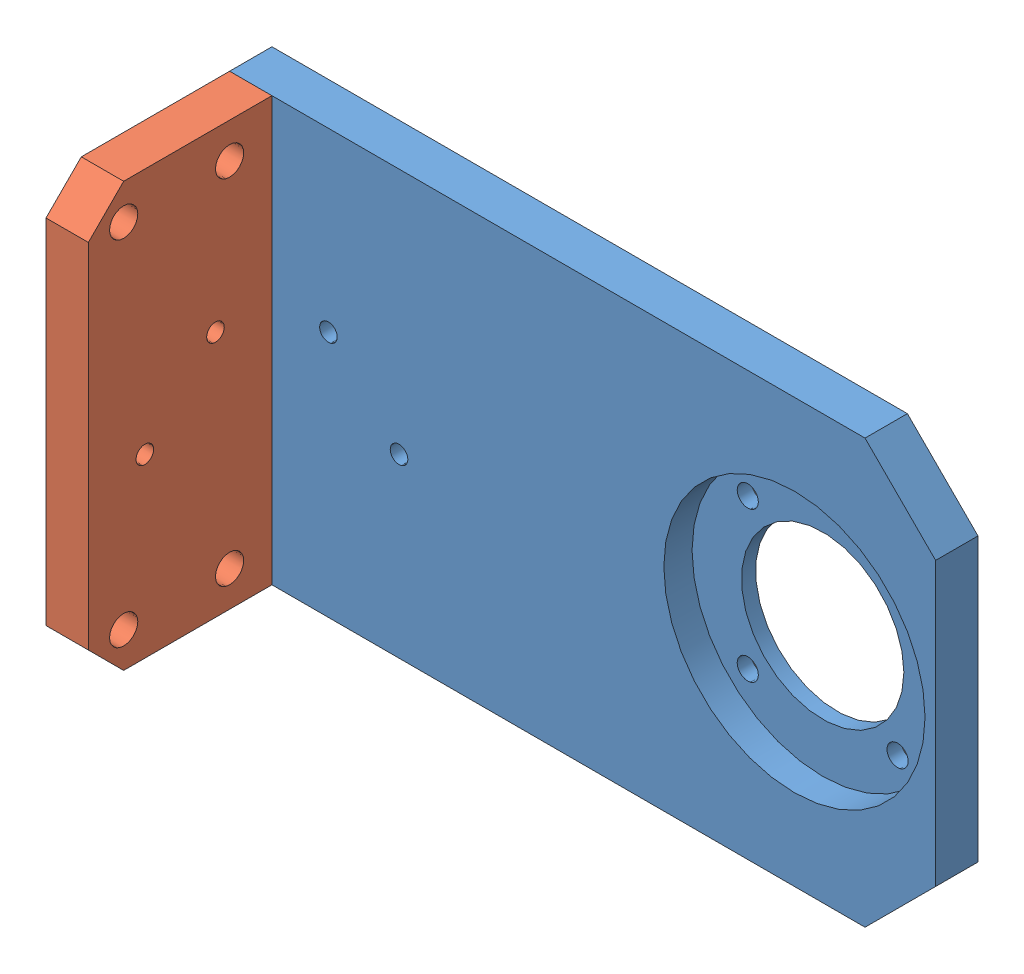
SolidWorks assembly 左右电机安装板, configuration 默认. Lengths in mm.
Overall size (100 60 32.22).
2 component instances, 2 part files, 3 mates.
Components (placement in the parent):
- XY 方向固定板-1: XY 方向固定板 [默认] at (34.257 -39.3763 97.1078) size (100 60 6.22)
- XY 方向固定板2-1: XY 方向固定板2 [默认] at (-15.743 -39.3763 116.1078) x (0 0 -1) z (1 0 0) size (26 60 6)
Mates (geometry in assembly coordinates):
- 同心1: concentric aligned: cylinder of XY 方向固定板-1 through (-12.743 -59.3763 97.1078) axis (0 0 -1) radius 1.7; cylinder of XY 方向固定板2-1 through (-12.743 -59.3763 103.1078) axis (0 0 -1) radius 1.25
- 同心2: concentric aligned: cylinder of XY 方向固定板-1 through (-12.743 -19.3763 97.1078) axis (0 0 -1) radius 1.7; cylinder of XY 方向固定板2-1 through (-12.743 -19.3763 103.1078) axis (0 0 -1) radius 1.25
- 重合1: coincident anti-aligned: plane of XY 方向固定板-1 through (34.257 -39.3763 103.1078) normal (0 0 1); plane of XY 方向固定板2-1 through (-9.743 -69.3763 103.1078) normal (0 0 -1)
